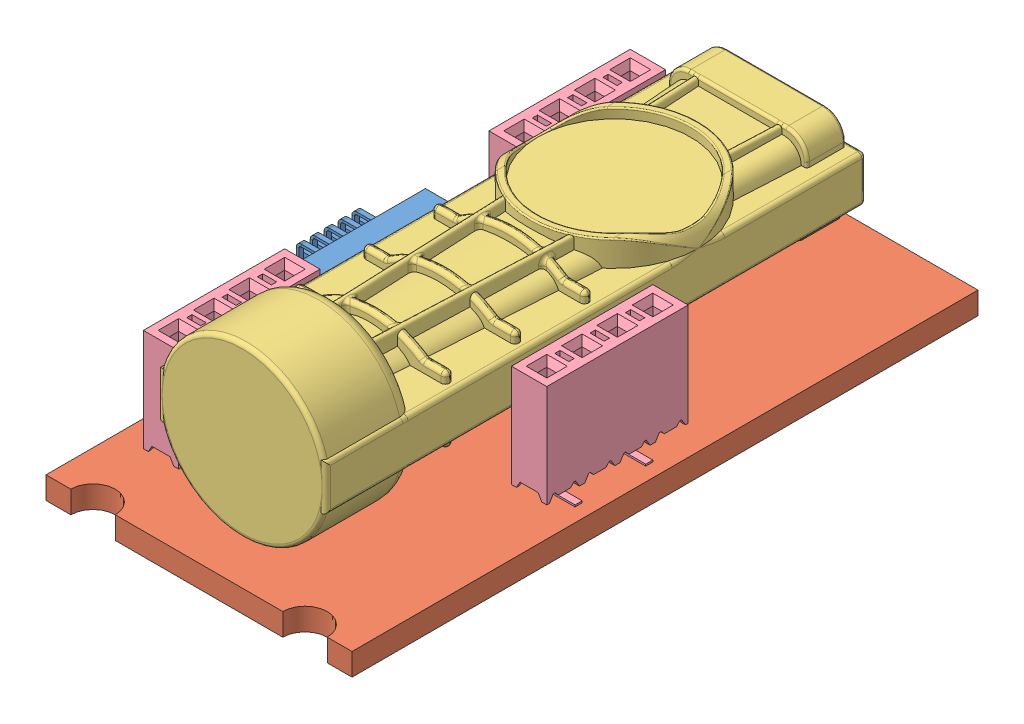
SolidWorks assembly EE891_+_Connector, configuration Default. Lengths in mm.
Overall size (26.57 17.48 45).
7 component instances, 4 part files, 8 mates.
Components (placement in the parent):
- MEC1-108-02-XX-D-RA1-SL-1: MEC1-108-02-XX-D-RA1-SL [Default] at (0 3.4036 0) x (0 -1 0) z (0 0 1) size (8.08 11.97 12.54)
- EE891-1: EE891 [Default] at (8.045 2.5146 0) x (0 0 1) z (-1 0 0) size (45 14.5 22)
  - EE891_PCB-1: EE891_PCB [Default] at origin size (45 1.6 22)
  - EE891_CO2-1: EE891_CO2 [Default] at (0 7.65 0) size (38.8 14.5 12.1)
  - EE891_CON-1: EE891_CON [Default] at (-12.42 1.727 7.73) size (10.16 7.49 4.57)
  - EE891_CON-2: EE891_CON [Default] at (12.42 1.727 7.73) size (10.16 7.49 4.57)
  - EE891_CON-3: EE891_CON [Default] at (1.42 1.727 -7.73) size (10.16 7.49 4.57)
Mates (geometry in assembly coordinates):
- Coincident1: coincident anti-aligned: plane of MEC1-108-02-XX-D-RA1-SL-1 through (-4.445 0 6.27) normal (0 -1 0); plane of assembly through (0 0 0) normal (0 1 0)
- Coincident2: coincident: point of MEC1-108-02-XX-D-RA1-SL-1; plane of assembly
- Coincident3: coincident: point of MEC1-108-02-XX-D-RA1-SL-1; plane of assembly
- Parallel1: parallel aligned: plane of MEC1-108-02-XX-D-RA1-SL-1 through (4.445 6.8072 6.27) normal (1 0 0); plane of assembly
- Coincident5: coincident aligned: plane of ? through (11.9608 2.5146 0) normal (0 0 1)
- Parallel2: parallel aligned: plane of MEC1-108-02-XX-D-RA1-SL-1 through (4.445 6.8072 6.27) normal (0 1 0); plane of EE891-1/EE891_PCB-1 through (4.3408 4.1146 -22.5) normal (0 1 0)
- Coincident8: coincident anti-aligned: plane of MEC1-108-02-XX-D-RA1-SL-1 through (-3.683 2.5146 -5) normal (0 1 0); plane of EE891-1/EE891_PCB-1 through (4.3408 2.5146 -22.5) normal (0 -1 0)
- Distance2: distance = 0.2 mm anti-aligned: plane of MEC1-108-02-XX-D-RA1-SL-1 through (4.445 6.8072 6.27) normal (1 0 0); plane of EE891-1/EE891_PCB-1 through (4.645 4.1146 5.5) normal (-1 0 0)
